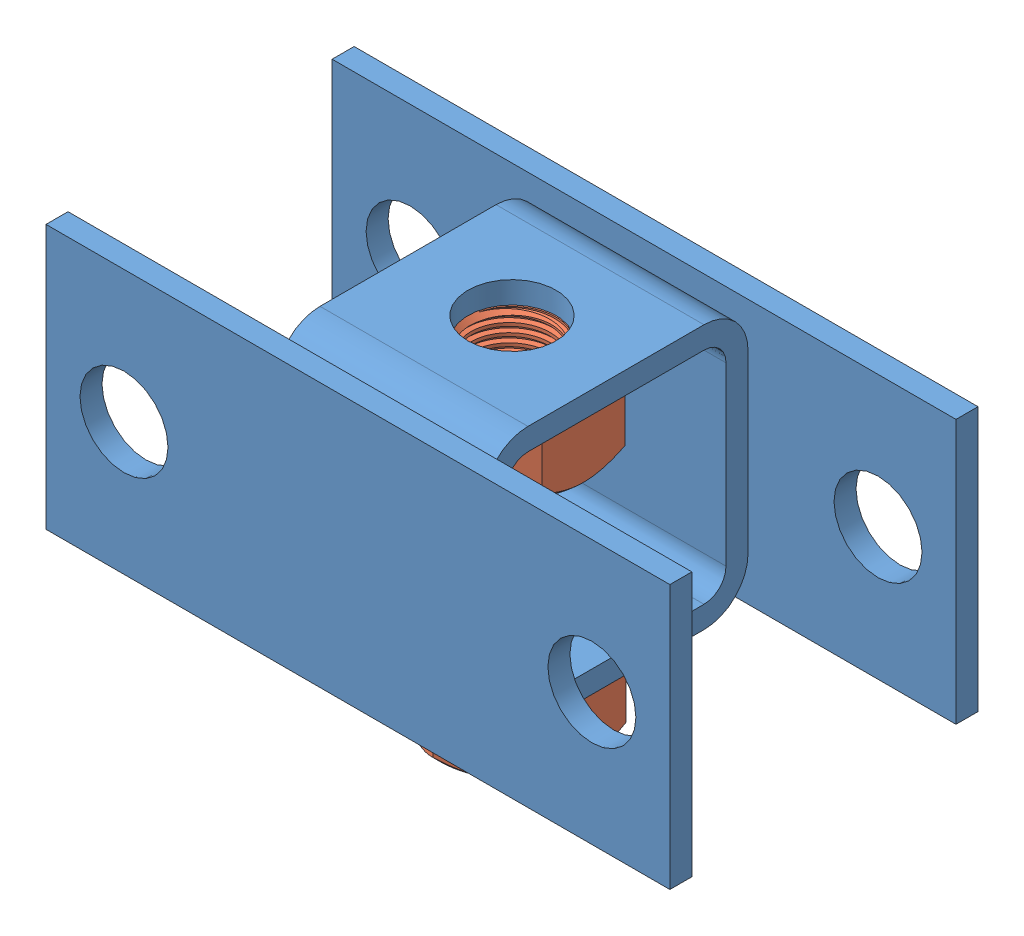
SolidWorks assembly Coupler-2 Assembly, configuration Default. Lengths in mm.
Overall size (180 101.54 88.9).
3 component instances, 2 part files, 4 mates.
Components (placement in the parent):
- Center Tube Coupler-2-1: Center Tube Coupler-2 [Default<As Machined>] at (58.2991 100.7931 138.1965) size (180 76.2 88.9)
- 94815A118_RIGHT-HAND GENERAL PURPOSE ACME HEX NUT-2: 94815A118_RIGHT-HAND GENERAL PURPOSE ACME HEX NUT [94815A118] at (88.2991 50.1915 138.1965) x (-0.537908 0 -0.843004) z (0 1 0) size (41.27 52.42 25.67)
- 94815A118_RIGHT-HAND GENERAL PURPOSE ACME HEX NUT-3: 94815A118_RIGHT-HAND GENERAL PURPOSE ACME HEX NUT [94815A118] at (88.2991 120.0415 138.1965) x (1 0 0) z (0 1 0) size (41.27 52.42 25.67)
Mates (geometry in assembly coordinates):
- Concentric2: concentric: circle of Center Tube Coupler-2-1; circle of 94815A118_RIGHT-HAND GENERAL PURPOSE ACME HEX NUT-2
- Coincident2: coincident: plane of Center Tube Coupler-2-1 through (118.2991 62.6931 112.7965) normal (0 -1 0); plane of 94815A118_RIGHT-HAND GENERAL PURPOSE ACME HEX NUT-2 through (108.388 62.6931 125.3781) normal (0 1 0)
- Concentric3: concentric: circle of Center Tube Coupler-2-1; circle of 94815A118_RIGHT-HAND GENERAL PURPOSE ACME HEX NUT-3
- Coincident3: coincident: plane of Center Tube Coupler-2-1 through (118.2991 132.5431 163.5965) normal (0 -1 0); plane of 94815A118_RIGHT-HAND GENERAL PURPOSE ACME HEX NUT-3 through (88.2991 132.5431 162.0266) normal (0 1 0)
